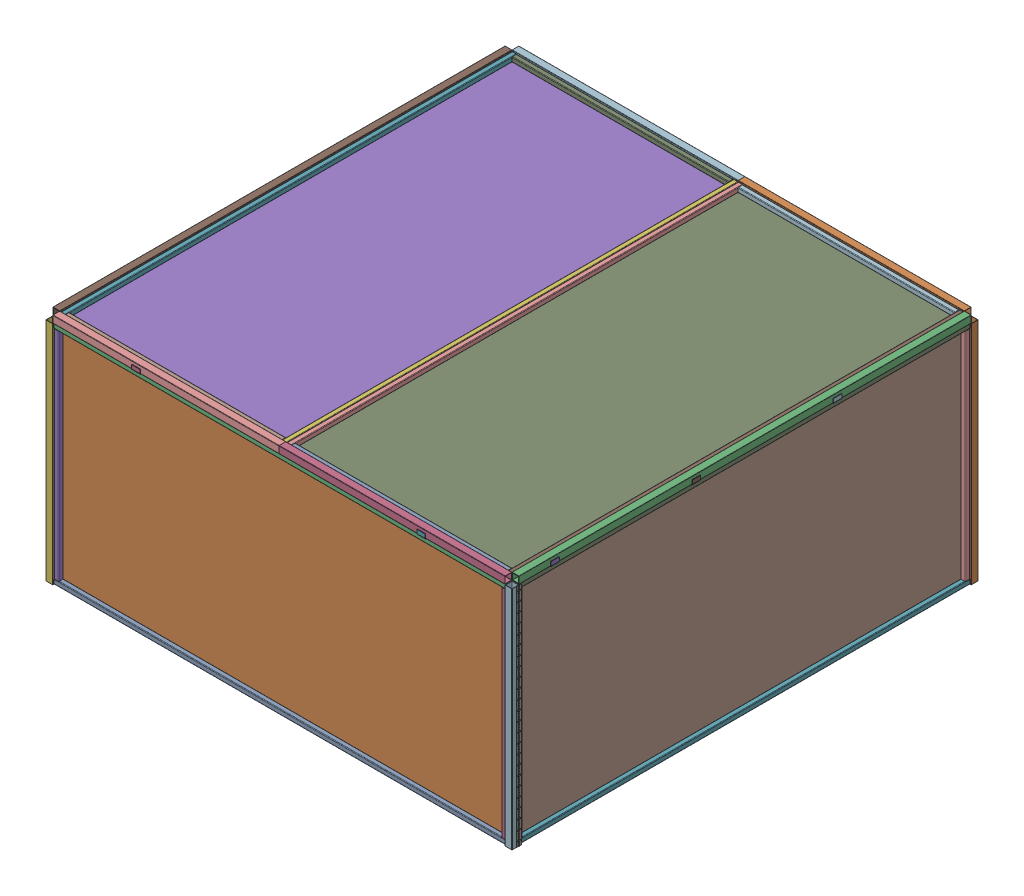
SolidWorks assembly Full Arena Assembly, configuration Default. Lengths in mm.
Overall size (2520.95 1260.47 2520.95).
86 component instances, 9 part files, 25 mates.
Components (placement in the parent):
- Wall Assembly-5: Wall Assembly [Default] at (38.1 0 25.4) size (2476.5 1222.38 41.27)
  - 8ft 1in Steel Bar-1: 8ft 1in Steel Bar [1471T534] at (1219.2 12.7 -12.7) x (0 0 1) z (-1 0 0) size (25.4 25.4 2438.4)
  - Polycarbonate-1: Polycarbonate [8574K75] at (1219.2 609.6 -28.575) size (2438.4 1219.2 6.35)
  - 8ft 1in Steel Bar-2: 8ft 1in Steel Bar [1471T534] at (1219.2 1206.5 -12.7) x (0 0 1) z (1 0 0) size (25.4 25.4 2438.4)
  - 46in 1in Steel Bar-1: 46in 1in Steel Bar [1471T532] at (2425.7 584.2 -12.7) x (1 0 0) z (0 1 0) size (25.4 25.4 1168.4)
  - 46in 1in Steel Bar-2: 46in 1in Steel Bar [1471T532] at (12.7 584.2 -12.7) x (1 0 0) z (0 1 0) size (25.4 25.4 1168.4)
  - 4ft 1.5in Steel Bar-1: 4ft 1.5in Steel Bar [6527K573] at (-19.05 914.4 -12.7) x (0 -1 0) z (1 0 0) size (1219.2 38.1 38.1)
  - Corner Bracket-1: Corner Bracket [2313N38] at (47.625 1171.575 -34.925) x (0 0 1) z (0 -1 0) size (25.4 44.45 50.8)
  - Corner Bracket-2: Corner Bracket [2313N38] at (835.2367 1171.575 -34.925) x (0 0 1) z (0 -1 0) size (25.4 44.45 50.8)
  - Corner Bracket-3: Corner Bracket [2313N38] at (1622.8483 1171.575 -34.925) x (0 0 1) z (0 -1 0) size (25.4 44.45 50.8)
  - Corner Bracket-4: Corner Bracket [2313N38] at (2410.46 1171.575 -34.925) x (0 0 1) z (0 -1 0) size (25.4 44.45 50.8)
- Wall Assembly-6: Wall Assembly [Default] at (6.35 0 -2444.75) x (0 0 1) z (-1 0 0) size (2476.5 1222.38 41.27)
  - 8ft 1in Steel Bar-1: 8ft 1in Steel Bar [1471T534] at (1219.2 12.7 -12.7) x (0 0 1) z (-1 0 0) size (25.4 25.4 2438.4)
  - Polycarbonate-1: Polycarbonate [8574K75] at (1219.2 609.6 -28.575) size (2438.4 1219.2 6.35)
  - 8ft 1in Steel Bar-2: 8ft 1in Steel Bar [1471T534] at (1219.2 1206.5 -12.7) x (0 0 1) z (1 0 0) size (25.4 25.4 2438.4)
  - 46in 1in Steel Bar-1: 46in 1in Steel Bar [1471T532] at (2425.7 584.2 -12.7) x (1 0 0) z (0 1 0) size (25.4 25.4 1168.4)
  - 46in 1in Steel Bar-2: 46in 1in Steel Bar [1471T532] at (12.7 584.2 -12.7) x (1 0 0) z (0 1 0) size (25.4 25.4 1168.4)
  - 4ft 1.5in Steel Bar-1: 4ft 1.5in Steel Bar [6527K573] at (-19.05 914.4 -12.7) x (0 -1 0) z (1 0 0) size (1219.2 38.1 38.1)
  - Corner Bracket-1: Corner Bracket [2313N38] at (47.625 1171.575 -34.925) x (0 0 1) z (0 -1 0) size (25.4 44.45 50.8)
  - Corner Bracket-2: Corner Bracket [2313N38] at (835.2367 1171.575 -34.925) x (0 0 1) z (0 -1 0) size (25.4 44.45 50.8)
  - Corner Bracket-3: Corner Bracket [2313N38] at (1622.8483 1171.575 -34.925) x (0 0 1) z (0 -1 0) size (25.4 44.45 50.8)
  - Corner Bracket-4: Corner Bracket [2313N38] at (2410.46 1171.575 -34.925) x (0 0 1) z (0 -1 0) size (25.4 44.45 50.8)
- Wall Assembly-7: Wall Assembly [Default] at (2476.5 0 -2476.5) x (-1 0 0) z (0 0 -1) size (2476.5 1222.38 41.27)
  - 8ft 1in Steel Bar-1: 8ft 1in Steel Bar [1471T534] at (1219.2 12.7 -12.7) x (0 0 1) z (-1 0 0) size (25.4 25.4 2438.4)
  - Polycarbonate-1: Polycarbonate [8574K75] at (1219.2 609.6 -28.575) size (2438.4 1219.2 6.35)
  - 8ft 1in Steel Bar-2: 8ft 1in Steel Bar [1471T534] at (1219.2 1206.5 -12.7) x (0 0 1) z (1 0 0) size (25.4 25.4 2438.4)
  - 46in 1in Steel Bar-1: 46in 1in Steel Bar [1471T532] at (2425.7 584.2 -12.7) x (1 0 0) z (0 1 0) size (25.4 25.4 1168.4)
  - 46in 1in Steel Bar-2: 46in 1in Steel Bar [1471T532] at (12.7 584.2 -12.7) x (1 0 0) z (0 1 0) size (25.4 25.4 1168.4)
  - 4ft 1.5in Steel Bar-1: 4ft 1.5in Steel Bar [6527K573] at (-19.05 914.4 -12.7) x (0 -1 0) z (1 0 0) size (1219.2 38.1 38.1)
  - Corner Bracket-1: Corner Bracket [2313N38] at (47.625 1171.575 -34.925) x (0 0 1) z (0 -1 0) size (25.4 44.45 50.8)
  - Corner Bracket-2: Corner Bracket [2313N38] at (835.2367 1171.575 -34.925) x (0 0 1) z (0 -1 0) size (25.4 44.45 50.8)
  - Corner Bracket-3: Corner Bracket [2313N38] at (1622.8483 1171.575 -34.925) x (0 0 1) z (0 -1 0) size (25.4 44.45 50.8)
  - Corner Bracket-4: Corner Bracket [2313N38] at (2410.46 1171.575 -34.925) x (0 0 1) z (0 -1 0) size (25.4 44.45 50.8)
- Wall Assembly-8: Wall Assembly [Default] at (2508.25 0 -6.35) x (0 0 -1) z (1 0 0) size (2476.5 1222.38 41.27)
  - 8ft 1in Steel Bar-1: 8ft 1in Steel Bar [1471T534] at (1219.2 12.7 -12.7) x (0 0 1) z (-1 0 0) size (25.4 25.4 2438.4)
  - Polycarbonate-1: Polycarbonate [8574K75] at (1219.2 609.6 -28.575) size (2438.4 1219.2 6.35)
  - 8ft 1in Steel Bar-2: 8ft 1in Steel Bar [1471T534] at (1219.2 1206.5 -12.7) x (0 0 1) z (1 0 0) size (25.4 25.4 2438.4)
  - 46in 1in Steel Bar-1: 46in 1in Steel Bar [1471T532] at (2425.7 584.2 -12.7) x (1 0 0) z (0 1 0) size (25.4 25.4 1168.4)
  - 46in 1in Steel Bar-2: 46in 1in Steel Bar [1471T532] at (12.7 584.2 -12.7) x (1 0 0) z (0 1 0) size (25.4 25.4 1168.4)
  - 4ft 1.5in Steel Bar-1: 4ft 1.5in Steel Bar [6527K573] at (-19.05 914.4 -12.7) x (0 -1 0) z (1 0 0) size (1219.2 38.1 38.1)
  - Corner Bracket-1: Corner Bracket [2313N38] at (47.625 1171.575 -34.925) x (0 0 1) z (0 -1 0) size (25.4 44.45 50.8)
  - Corner Bracket-2: Corner Bracket [2313N38] at (835.2367 1171.575 -34.925) x (0 0 1) z (0 -1 0) size (25.4 44.45 50.8)
  - Corner Bracket-3: Corner Bracket [2313N38] at (1622.8483 1171.575 -34.925) x (0 0 1) z (0 -1 0) size (25.4 44.45 50.8)
  - Corner Bracket-4: Corner Bracket [2313N38] at (2410.46 1171.575 -34.925) x (0 0 1) z (0 -1 0) size (25.4 44.45 50.8)
- Roof Assembly-1: Roof Assembly [Default] at (38.1 1222.375 -6.35) x (0 0 1) z (-1 0 0) size (2520.95 41.27 1263.65)
  - Polycarbonate-1: Polycarbonate [8574K75] at (-1219.2 3.175 -609.6) x (1 0 0) z (0 -1 0) size (2438.4 1219.2 6.35)
  - 8ft 1in Steel Bar-1: 8ft 1in Steel Bar [1471T534] at (-1219.2 19.05 -1206.5) x (0 0 1) z (-1 0 0) size (25.4 25.4 2438.4)
  - 8ft 1in Steel Bar-2: 8ft 1in Steel Bar [1471T534] at (-1219.2 19.05 -12.7) x (0 0 1) z (-1 0 0) size (25.4 25.4 2438.4)
  - 46in 1in Steel Bar-1: 46in 1in Steel Bar [1471T532] at (-12.7 19.05 -635) size (25.4 25.4 1168.4)
  - 46in 1in Steel Bar-2: 46in 1in Steel Bar [1471T532] at (-2425.7 19.05 -635) size (25.4 25.4 1168.4)
  - 4ft 1.5in Steel Bar-1: 4ft 1.5in Steel Bar [6527K573] at (19.05 19.05 -304.8) x (0 0 -1) z (1 0 0) size (1219.2 38.1 38.1)
  - 8ft 1.5in Steel Bar-1: 8ft 1.5in Steel Bar [1984N13] at (-1219.2 19.05 19.05) x (0 0 1) z (-1 0 0) size (38.1 38.1 2438.4)
  - 4ft 1.5in Steel Bar-3: 4ft 1.5in Steel Bar [6527K573] at (-2457.45 19.05 -304.8) x (0 0 -1) z (0 -1 0) size (1219.2 38.1 38.1)
  - Corner Bracket-1: Corner Bracket [2313N38] at (-2246.5399 -3.175 -9.525) x (0 1 0) z (0 0 -1) size (25.4 44.45 50.8)
  - Corner Bracket-2: Corner Bracket [2313N38] at (-2246.5399 -3.175 -1171.575) x (0 1 0) z (0 0 1) size (25.4 44.45 50.8)
  - Corner Bracket-7: Corner Bracket [2313N38] at (-2428.875 -3.175 -449.8508) x (0 1 0) z (1 0 0) size (25.4 44.45 50.8)
  - Corner Bracket-8: Corner Bracket [2313N38] at (-9.525 -3.175 -449.8508) x (0 1 0) z (-1 0 0) size (25.4 44.45 50.8)
  - Corner Bracket-3: Corner Bracket [2313N38] at (-1484.5399 -3.175 -1171.575) x (0 1 0) z (0 0 1) size (25.4 44.45 50.8)
  - Corner Bracket-4: Corner Bracket [2313N38] at (-722.5399 -3.175 -1171.575) x (0 1 0) z (0 0 1) size (25.4 44.45 50.8)
  - Corner Bracket-5: Corner Bracket [2313N38] at (-1484.5399 -3.175 -9.525) x (0 1 0) z (0 0 -1) size (25.4 44.45 50.8)
  - Corner Bracket-6: Corner Bracket [2313N38] at (-722.5399 -3.175 -9.525) x (0 1 0) z (0 0 -1) size (25.4 44.45 50.8)
- Roof Assembly-2: Roof Assembly [Default] at (2476.5 1222.375 -2444.75) x (0 0 -1) z (1 0 0) size (2520.95 41.27 1263.65)
  - Polycarbonate-1: Polycarbonate [8574K75] at (-1219.2 3.175 -609.6) x (1 0 0) z (0 -1 0) size (2438.4 1219.2 6.35)
  - 8ft 1in Steel Bar-1: 8ft 1in Steel Bar [1471T534] at (-1219.2 19.05 -1206.5) x (0 0 1) z (-1 0 0) size (25.4 25.4 2438.4)
  - 8ft 1in Steel Bar-2: 8ft 1in Steel Bar [1471T534] at (-1219.2 19.05 -12.7) x (0 0 1) z (-1 0 0) size (25.4 25.4 2438.4)
  - 46in 1in Steel Bar-1: 46in 1in Steel Bar [1471T532] at (-12.7 19.05 -635) size (25.4 25.4 1168.4)
  - 46in 1in Steel Bar-2: 46in 1in Steel Bar [1471T532] at (-2425.7 19.05 -635) size (25.4 25.4 1168.4)
  - 4ft 1.5in Steel Bar-1: 4ft 1.5in Steel Bar [6527K573] at (19.05 19.05 -304.8) x (0 0 -1) z (1 0 0) size (1219.2 38.1 38.1)
  - 8ft 1.5in Steel Bar-1: 8ft 1.5in Steel Bar [1984N13] at (-1219.2 19.05 19.05) x (0 0 1) z (-1 0 0) size (38.1 38.1 2438.4)
  - 4ft 1.5in Steel Bar-3: 4ft 1.5in Steel Bar [6527K573] at (-2457.45 19.05 -304.8) x (0 0 -1) z (0 -1 0) size (1219.2 38.1 38.1)
  - Corner Bracket-1: Corner Bracket [2313N38] at (-2246.5399 -3.175 -9.525) x (0 1 0) z (0 0 -1) size (25.4 44.45 50.8)
  - Corner Bracket-2: Corner Bracket [2313N38] at (-2246.5399 -3.175 -1171.575) x (0 1 0) z (0 0 1) size (25.4 44.45 50.8)
  - Corner Bracket-7: Corner Bracket [2313N38] at (-2428.875 -3.175 -449.8508) x (0 1 0) z (1 0 0) size (25.4 44.45 50.8)
  - Corner Bracket-8: Corner Bracket [2313N38] at (-9.525 -3.175 -449.8508) x (0 1 0) z (-1 0 0) size (25.4 44.45 50.8)
  - Corner Bracket-3: Corner Bracket [2313N38] at (-1484.5399 -3.175 -1171.575) x (0 1 0) z (0 0 1) size (25.4 44.45 50.8)
  - Corner Bracket-4: Corner Bracket [2313N38] at (-722.5399 -3.175 -1171.575) x (0 1 0) z (0 0 1) size (25.4 44.45 50.8)
  - Corner Bracket-5: Corner Bracket [2313N38] at (-1484.5399 -3.175 -9.525) x (0 1 0) z (0 0 -1) size (25.4 44.45 50.8)
  - Corner Bracket-6: Corner Bracket [2313N38] at (-722.5399 -3.175 -9.525) x (0 1 0) z (0 0 -1) size (25.4 44.45 50.8)
- Floor Assembly-1: Floor Assembly [Default] at (38.1 0 -6.35) x (0 0 1) z (-1 0 0) size (2438.4 152.4 2438.4)
  - 2x6-1: 2x6 [Default] at (-2438.4 152.4 -2400.3) x (0 -1 0) z (1 0 0) size (139.7 38.1 2400.3)
  - 2x6-2: 2x6 [Default] at (-2438.4 152.4 -2400.3) x (0 -1 0) z (0 0 1) size (139.7 38.1 2400.3)
  - 2x6-3: 2x6 [Default] at (-2400.3 152.4 0) x (0 -1 0) z (1 0 0) size (139.7 38.1 2400.3)
  - 2x6-4: 2x6 [Default] at (-38.1 152.4 -2438.4) x (0 -1 0) z (0 0 1) size (139.7 38.1 2400.3)
  - Sub Floor-1: Sub Floor [Default] at (-2438.4 0 -1219.2) size (2438.4 12.7 1219.2)
  - Sub Floor-2: Sub Floor [Default] at (-2438.4 0 0) size (2438.4 12.7 1219.2)
- Hinge-1: Hinge [1569A103] at (2516.0351 609.6 -4.9149) x (0 -1 0) z (1 0 0) size (1219.2 25.4 2.87)
Mates (geometry in assembly coordinates):
- Coincident2: coincident aligned: plane of SingleWall-5/8574K75_Clear Impact-Resistant Polycarbonate-1 through (1257.3 609.6 0) normal (0 0 1)
- Coincident3: coincident anti-aligned: plane of SingleWall-5/6527K573_Low-Carbon Steel Rectangular Tube-1 through (0 0 29.845) normal (-1 0 0)
- Coincident4: coincident anti-aligned: plane of SingleWall-5/6527K573_Low-Carbon Steel Rectangular Tube-1 through (1.905 0 29.845) normal (0 -1 0)
- Coincident5: coincident anti-aligned: plane of SingleWall-5/6527K573_Low-Carbon Steel Rectangular Tube-1 through (1.905 0 -6.35) normal (0 0 -1); plane of SingleWall-6/46in Steel Bar-1 through (6.35 1193.8 -6.35) normal (0 0 1)
- Coincident6: coincident aligned: plane of SingleWall-5/8ft Steel Bar-2 through (2476.5 1219.2 25.4) normal (0 1 0); plane of SingleWall-6/8ft Steel Bar-2 through (6.35 1219.2 -6.35) normal (0 1 0)
- Coincident7: coincident aligned: plane of SingleWall-5/6527K573_Low-Carbon Steel Rectangular Tube-1 through (38.1 0 29.845) normal (1 0 0); plane of SingleWall-6/8574K75_Clear Impact-Resistant Polycarbonate-1 through (38.1 609.6 -1225.55) normal (1 0 0)
- Coincident8: coincident anti-aligned: plane of SingleWall-6/6527K573_Low-Carbon Steel Rectangular Tube-1 through (38.1 0 -2480.945) normal (1 0 0); plane of SingleWall-7/46in Steel Bar-1 through (38.1 1193.8 -2476.5) normal (-1 0 0)
- Coincident9: coincident aligned: plane of SingleWall-6/8ft Steel Bar-2 through (6.35 1219.2 -6.35) normal (0 1 0); plane of SingleWall-7/8ft Steel Bar-2 through (38.1 1219.2 -2476.5) normal (0 1 0)
- Coincident10: coincident aligned: plane of SingleWall-6/6527K573_Low-Carbon Steel Rectangular Tube-1 through (1.905 0 -2444.75) normal (0 0 1); plane of SingleWall-7/8574K75_Clear Impact-Resistant Polycarbonate-1 through (1257.3 609.6 -2444.75) normal (0 0 1)
- Coincident12: coincident aligned: plane of SingleWall-7/8ft Steel Bar-2 through (38.1 1219.2 -2476.5) normal (0 1 0); plane of SingleWall-8/8ft Steel Bar-2 through (2508.25 1219.2 -2444.75) normal (0 1 0)
- Coincident13: coincident anti-aligned: plane of SingleWall-7/6527K573_Low-Carbon Steel Rectangular Tube-1 through (2512.695 0 -2444.75) normal (0 0 1); plane of SingleWall-8/46in Steel Bar-1 through (2508.25 1193.8 -2444.75) normal (0 0 -1)
- Coincident14: coincident aligned: plane of SingleWall-7/6527K573_Low-Carbon Steel Rectangular Tube-1 through (2476.5 0 -2480.945) normal (-1 0 0); plane of SingleWall-8/8574K75_Clear Impact-Resistant Polycarbonate-1 through (2476.5 609.6 -1225.55) normal (-1 0 0)
- Coincident16: coincident anti-aligned: plane of SingleWall-6/8574K75_Clear Impact-Resistant Polycarbonate-1 through (38.1 609.6 -1225.55) normal (1 0 0); plane of Roof Section-1/6527K573_Low-Carbon Steel Rectangular Tube-3 through (38.1 1434.9066 -2444.75) normal (-1 0 0)
- Coincident17: coincident aligned: plane of SingleWall-6/6527K573_Low-Carbon Steel Rectangular Tube-1 through (1.905 0 -2482.85) normal (0 0 -1); plane of Roof Section-1/6527K573_Low-Carbon Steel Rectangular Tube-3 through (1257.3 1433.0016 -2482.85) normal (0 0 -1)
- Coincident19: coincident aligned: plane of SingleWall-7/6527K573_Low-Carbon Steel Rectangular Tube-1 through (2514.6 0 -2480.945) normal (1 0 0); plane of Roof Section-2/1984N13_Weld-Together Framing Rail-1 through (2514.6 1396.8066 -6.35) normal (1 0 0)
- Coincident20: coincident aligned: plane of SingleWall-7/6527K573_Low-Carbon Steel Rectangular Tube-1 through (2512.695 0 -2482.85) normal (0 0 -1); plane of Roof Section-2/6527K573_Low-Carbon Steel Rectangular Tube-1 through (1257.3 1398.7116 -2482.85) normal (0 0 -1)
- Coincident26: coincident anti-aligned: plane of SingleWall-7/8574K75_Clear Impact-Resistant Polycarbonate-1 through (1257.3 609.6 -2444.75) normal (0 0 1); plane of Floor-1/2 by 6-2 through (0 152.4 -2444.75) normal (0 0 -1)
- Coincident27: coincident aligned: plane of SingleWall-8/8ft Steel Bar-1 through (2508.25 0 -6.35) normal (0 -1 0); plane of Floor-1/Plywood Base-1 through (1257.3 0 -2444.75) normal (0 -1 0)
- Coincident28: coincident anti-aligned: plane of SingleWall-8/8574K75_Clear Impact-Resistant Polycarbonate-1 through (2476.5 609.6 -1225.55) normal (-1 0 0); plane of Floor-1/2 by 6-1 through (2476.5 152.4 -6.35) normal (1 0 0)
- Parallel1: parallel anti-aligned: line of Wall Assembly-8/8ft 1in Steel Bar-2 through (2508.25 1216.025 -6.35) axis (0 -1 0); line of Hinge-1 through (2514.6 1200.15 -6.35) axis (0 1 0)
- Coincident34: coincident aligned: line of Roof Assembly-2/8ft 1.5in Steel Bar-1 through (2514.6 1398.3306 -6.35) axis (0 1 0); line of Hinge-1 through (2514.6 1212.85 -6.35) axis (0 1 0)
- Coincident35: coincident anti-aligned: plane of Wall Assembly-8/4ft 1.5in Steel Bar-1 through (2514.6 0 29.845) normal (1 0 0); plane of Hinge-1 through (2514.6 0 7.7851) normal (-1 0 0)
- Coincident36: coincident aligned: plane of Wall Assembly-8/4ft 1.5in Steel Bar-1 through (2476.5 1219.2 31.75) normal (0 1 0); plane of Hinge-1 through (2516.0351 1219.2 -4.9149) normal (0 1 0)
- Coincident37: coincident aligned: plane of Roof Assembly-1/8ft 1in Steel Bar-1 through (1231.9 1428.5566 -2444.75) normal (0 1 0); plane of Roof Assembly-2/8ft 1in Steel Bar-1 through (1282.7 1428.5566 -6.35) normal (0 1 0)
- Coincident38: coincident anti-aligned: plane of Wall Assembly-7/8ft 1in Steel Bar-2 through (38.1 1219.2 -2476.5) normal (0 1 0); plane of Roof Assembly-2/Corner Bracket-8 through (2048.8742 1219.2 -2435.225) normal (0 -1 0)
